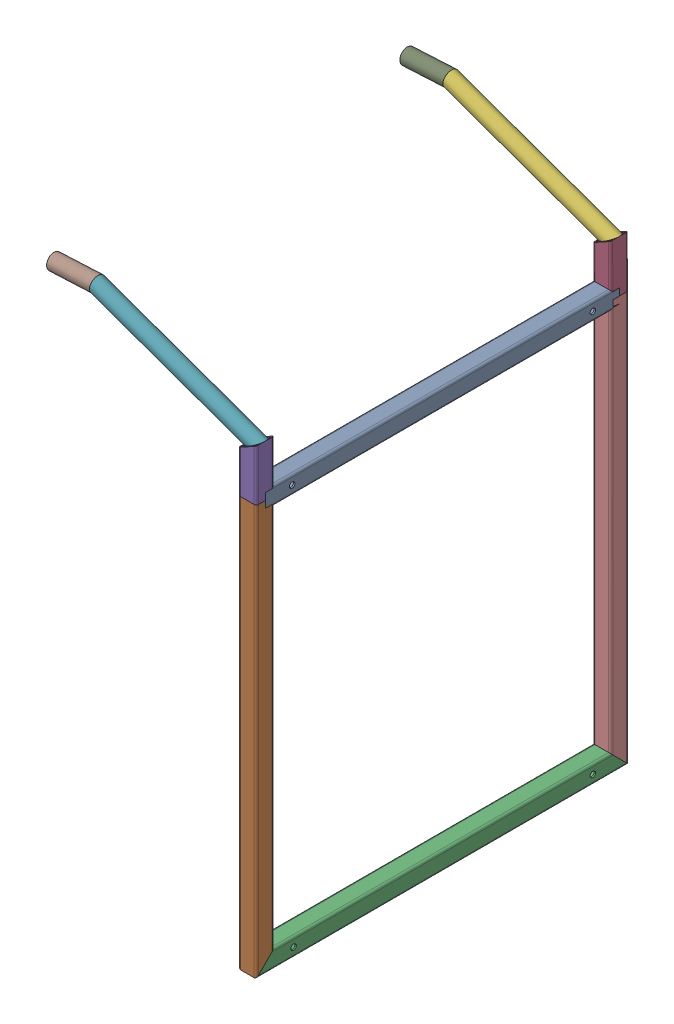
SolidWorks assembly Frame0002-1.stp, configuration Default. Lengths in mm.
Overall size (296.81 728.39 520).
10 component instances, 10 part files, 0 mates.
Components (placement in the parent):
- DIN 25 x 25 x 2 00000012.stp-1: DIN 25 x 25 x 2 00000012.stp [Default] at (-65.1046 -155.3691 235) x (1 0 0) z (0 0 -1) size (25.01 25.01 495)
- DIN 25 x 25 x 2 00000013.stp-1: DIN 25 x 25 x 2 00000013.stp [Default] at (-65.1046 -715.3691 235) x (1 0 0) z (0 1 0) size (25 25 572.5)
- DIN 25 x 25 x 2 00000014.stp-1: DIN 25 x 25 x 2 00000014.stp [Default] at (-65.1046 -715.3691 -260) size (25 25 520)
- DIN 25 x 25 x 2 00000015.stp-1: DIN 25 x 25 x 2 00000015.stp [Default] at (-65.1046 -155.3691 -260) x (0.999989 0.004781 0) z (-0.004781 0.999989 0.000001) size (25 25 71.78)
- DIN 25 x 25 x 2 00000016.stp-1: DIN 25 x 25 x 2 00000016.stp [Default] at (-65.1046 -155.3691 235) x (1 0 0) z (0 1 0) size (25 25 71.83)
- DIN 21,3 x 2,3 00000025.stp-1: DIN 21,3 x 2,3 00000025.stp [Default] at (-65.4154 -90.3699 -260) x (0 0 1) z (-0.941317 0.337523 0) size (21.3 21.3 249.01)
- DIN 21,3 x 2,3 00000026.stp-1: DIN 21,3 x 2,3 00000026.stp [Default] at (-287.6074 -10.5859 235) x (0 0 -1) z (0.941315 -0.337529 0) size (21.3 21.3 247.97)
- DIN 21,3 x 2,3 00000027.stp-1: DIN 21,3 x 2,3 00000027.stp [Default] at (-347.5293 -13.6372 234.7515) x (0.004137 0.00021 -0.999991) z (0.998697 0.050855 0.004142) size (21.3 21.3 62.13)
- DIN 21,3 x 2,3 00000030.stp-1: DIN 21,3 x 2,3 00000030.stp [Default] at (-288.9276 -10.2246 -259.9999) x (0.002102 0.000106 0.999998) z (-0.998703 -0.050862 0.002104) size (21.3 21.3 62.13)
- DIN 25 x 25 x 2 00000034-0.stp-1: DIN 25 x 25 x 2 00000034-0.stp [Default] at (-65.1046 -715.3691 -260) x (1 0 0) z (0 1 0) size (25 25 572.5)
